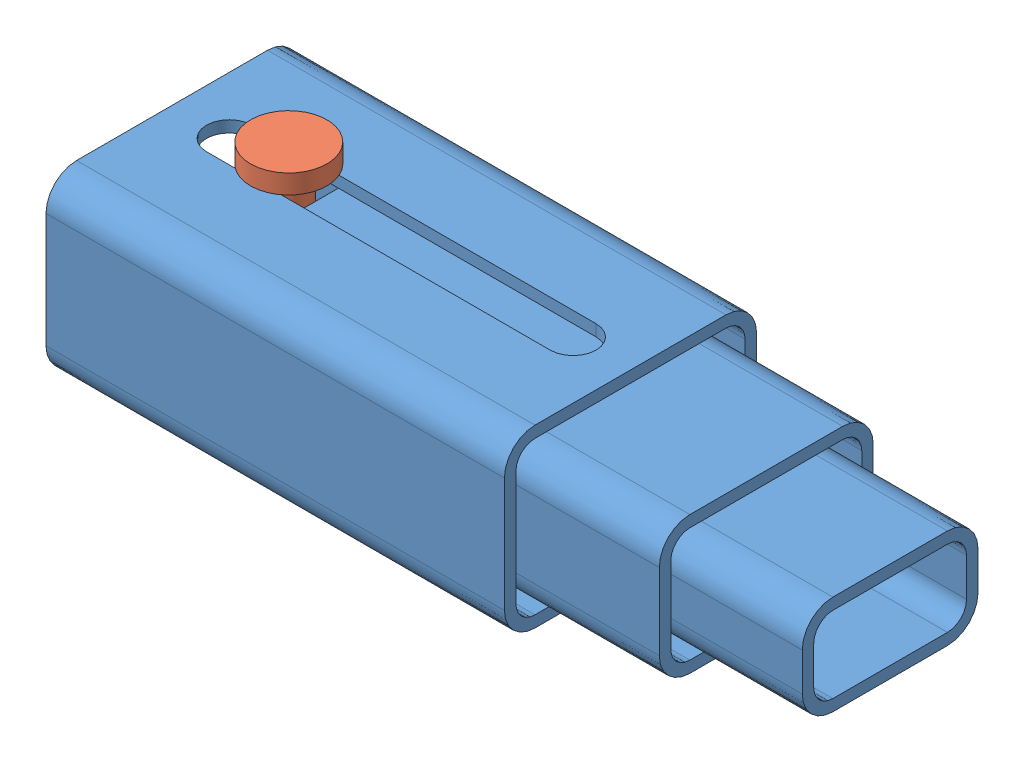
SolidWorks assembly Advanced & Mechanical Mates Assembly, configuration Default. Lengths in mm.
Overall size (187.98 60 66).
4 component instances, 2 part files, 9 mates.
Components (placement in the parent):
- nesting rectangles-1: nesting rectangles [Large] at (35.2454 77.1741 87.2622) size (120 46 66)
- nesting rectangles-2: nesting rectangles [Medium] at (70.7937 77.1741 87.2622) size (120 36 56)
- nesting rectangles-3: nesting rectangles [Small] at (103.2205 77.1741 87.2622) size (120 26 46)
- pin for mech mates-1: pin for mech mates [Default] at (5.7937 77.1741 87.2622) x (0.81536 0 0.578954) z (-0.578954 0 0.81536) size (20 60 20)
Mates (geometry in assembly coordinates):
- Width1: width anti-aligned: plane of nesting rectangles-1 through (95.2454 97.1741 112.2622) normal (0 -1 0); plane of nesting rectangles-1 through (95.2454 57.1741 112.2622) normal (0 1 0); plane of nesting rectangles-2 through (130.7937 95.1741 67.2622) normal (0 1 0); plane of nesting rectangles-2 through (130.7937 59.1741 67.2622) normal (0 -1 0)
- Width2: width aligned: plane of nesting rectangles-1 through (95.2454 62.1741 57.2622) normal (0 0 1); plane of nesting rectangles-1 through (95.2454 62.1741 117.2622) normal (0 0 -1); plane of nesting rectangles-2 through (130.7937 87.1741 115.2622) normal (0 0 1); plane of nesting rectangles-2 through (130.7937 87.1741 59.2622) normal (0 0 -1)
- Width3: width aligned: plane of nesting rectangles-2 through (130.7937 62.1741 107.2622) normal (0 1 0); plane of nesting rectangles-2 through (130.7937 92.1741 107.2622) normal (0 -1 0); plane of nesting rectangles-3 through (163.2205 90.1741 72.2622) normal (0 1 0); plane of nesting rectangles-3 through (163.2205 64.1741 72.2622) normal (0 -1 0)
- Width4: width aligned: plane of nesting rectangles-2 through (130.7937 67.1741 62.2622) normal (0 0 1); plane of nesting rectangles-2 through (130.7937 67.1741 112.2622) normal (0 0 -1); plane of nesting rectangles-3 through (163.2205 82.1741 110.2622) normal (0 0 1); plane of nesting rectangles-3 through (163.2205 82.1741 64.2622) normal (0 0 -1)
- Slot2: slot anti-aligned: cylinder of nesting rectangles-1; cylinder of pin for mech mates-1 through (5.7937 102.1741 87.2622) axis (0 -1 0) radius 5; cylinder of nesting rectangles-1 through (80.2454 54.1741 87.2622) axis (0 1 0) radius 6
- Linear/Linear Coupler2: linear coupler = 1 : 2 mm: plane of nesting rectangles-2 through (130.7937 87.1741 67.2622) normal (1 0 0); plane of nesting rectangles-3 through (163.2205 82.1741 72.2622) normal (1 0 0)
- Width5: width: plane of nesting rectangles-1 through (-9.7546 54.1741 81.2622) normal (0 0 1); plane of nesting rectangles-1 through (-9.7546 54.1741 93.2622) normal (0 0 -1); cylinder of pin for mech mates-1 through (5.7937 102.1741 87.2622) axis (0 -1 0) radius 5
- Tangent1: tangent anti-aligned: plane of nesting rectangles-2 through (10.7937 87.1741 67.2622) normal (-1 0 0); cylinder of pin for mech mates-1 through (5.7937 102.1741 87.2622) axis (0 -1 0) radius 5
- Width6: width anti-aligned: plane of pin for mech mates-1 through (5.7937 102.1741 87.2622) normal (0 -1 0); plane of pin for mech mates-1 through (5.7937 52.1741 87.2622) normal (0 1 0); plane of nesting rectangles-1 through (95.2454 100.1741 62.2622) normal (0 1 0); plane of nesting rectangles-1 through (95.2454 54.1741 62.2622) normal (0 -1 0)
